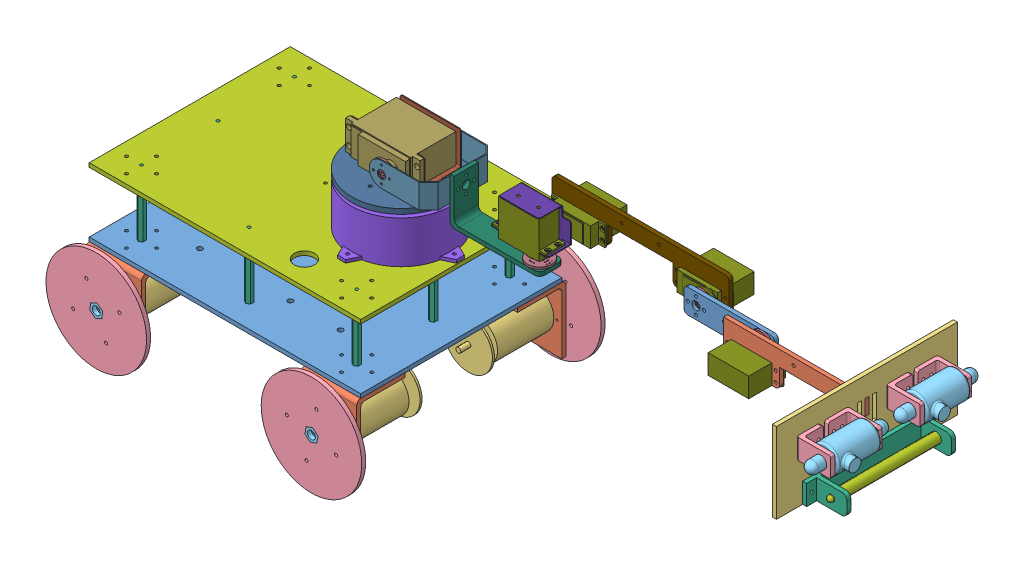
SolidWorks assembly robot, configuration Default. Lengths in mm.
Overall size (760.42 282.73 242).
55 component instances, 25 part files, 138 mates.
Components (placement in the parent):
- base_odroid_down_fix-1: base_odroid_down_fix [Default] at (39.4639 122.941 229.7749) x (1 0 0) z (0 -1 0) size (270 200 4)
- link_motor_1_port-1: link_motor_1_port [Default] at (221.3654 112.3394 287.3354) x (0 0 -1) z (1 0 0) size (48 66 56)
- motor_dc_NISCA-1: motor_dc_NISCA [Default] at (244.2642 39.7289 313.6416) x (0 -1 0) z (0 0 -1) size (54 48 92)
- roda_shaft-1: roda_shaft [Default] at (185.8398 121.6563 330.6416) x (-0.980223 0.197896 0) z (0 0 1) size (100 100 4)
- shaft_adapter_5mm-1: shaft_adapter_5mm [Default] at (248.7954 72.9583 317.6416) x (0.980223 -0.197896 0) z (0 0 1) size (12 13.86 17)
- link_motor_1_port-2: link_motor_1_port [Default] at (221.3654 112.3394 139.9479) x (0 0 1) z (-1 0 0) size (48 66 56)
- motor_dc_NISCA-2: motor_dc_NISCA [Default] at (198.4666 39.7289 113.6416) x (0 -1 0) z (0 0 1) size (54 48 92)
- shaft_adapter_5mm-3: shaft_adapter_5mm [Default] at (238.0112 59.5291 109.6416) x (0.404857 -0.91438 0) z (0 0 -1) size (12 13.86 17)
- roda_shaft-2: roda_shaft [Default] at (222.1063 135.748 96.6416) x (0.589448 0.807807 0) z (0 0 -1) size (100 100 4)
- link_motor_1_port-5: link_motor_1_port [Default] at (7.3654 112.3394 287.3354) x (0 0 -1) z (1 0 0) size (48 66 56)
- motor_dc_NISCA-5: motor_dc_NISCA [Default] at (-15.5334 128.1531 313.6416) x (0 1 0) z (0 0 -1) size (54 48 92)
- roda_shaft-5: roda_shaft [Default] at (51.5287 56.8466 334.6416) x (0.393495 -0.919327 0) z (0 0 -1) size (100 100 4)
- shaft_adapter_5mm-6: shaft_adapter_5mm [Default] at (0.8367 112.7577 317.6416) x (-0.393495 0.919327 0) z (0 0 1) size (12 13.86 17)
- link_motor_1_port-6: link_motor_1_port [Default] at (7.3654 112.3394 139.9479) x (0 0 1) z (-1 0 0) size (48 66 56)
- motor_dc_NISCA-6: motor_dc_NISCA [Default] at (-15.5334 39.7289 113.6416) x (0 -1 0) z (0 0 1) size (54 48 92)
- roda_shaft-6: roda_shaft [Default] at (45.258 48.6046 96.6416) x (0.202799 -0.97922 0) z (0 0 -1) size (100 100 4)
- shaft_adapter_5mm-7: shaft_adapter_5mm [Default] at (36.6325 79.8838 109.6416) x (0.949429 -0.313981 0) z (0 0 -1) size (12 13.86 17)
- spacer_6cm-2: spacer_6cm [Default] at (221.7099 182.941 288.7798) x (0.5 0 -0.866025) z (0 -1 0) size (6 6.93 68)
- spacer_6cm-3: spacer_6cm [Default] at (114.7099 182.941 288.7798) x (0.5 0 -0.866025) z (0 -1 0) size (6 6.93 68)
- spacer_6cm-4: spacer_6cm [Default] at (7.7099 182.941 288.7798) x (0.5 0 -0.866025) z (0 -1 0) size (6 6.93 68)
- spacer_6cm-5: spacer_6cm [Default] at (221.7099 182.941 212.7798) x (0.5 0 -0.866025) z (0 -1 0) size (6 6.93 68)
- spacer_6cm-7: spacer_6cm [Default] at (7.7099 182.941 212.7798) x (0.5 0 -0.866025) z (0 -1 0) size (6 6.93 68)
- spacer_6cm-8: spacer_6cm [Default] at (221.7099 182.941 136.7798) x (0.5 0 -0.866025) z (0 -1 0) size (6 6.93 68)
- spacer_6cm-9: spacer_6cm [Default] at (114.7099 182.941 136.7798) x (0.5 0 -0.866025) z (0 -1 0) size (6 6.93 68)
- spacer_6cm-10: spacer_6cm [Default] at (7.7099 182.941 136.7798) x (0.5 0 -0.866025) z (0 -1 0) size (6 6.93 68)
- base_odroid_up_fix-1: base_odroid_up_fix [Default] at (189.2669 186.941 197.5083) x (-1 0 0) z (0 -1 0) size (270 200 4)
- base_arm-1: base_arm [Default] at (189.3654 194.0898 219.4289) x (0 0 1) z (-1 0 0) size (118.01 42 118.01)
- servo_hs422-1: servo_hs422 [Default] at (199.6524 210.6756 203.7356) x (0 0 1) z (-1 0 0) size (19.81 42.14 58.23)
- link1_arm-1: link1_arm [Default] at (162.7148 232.0663 213.6416) x (-1 0 0) z (0 1 0) size (98 98 12)
- bracket_servo_hs755-1: bracket_servo_hs755 [Default] at (226.3654 266.4802 252.854) x (0 0 1) z (-1 0 0) size (44 34 74)
- servo_hs755-1: servo_hs755 [Default] at (199.4663 211.9363 188.6416) x (0 -1 0) z (0 0 1) size (29 74 56.99)
- servo_horn_general-1: servo_horn_general [Default] at (158.1724 253.8913 247.6316) x (-1 0 0) z (0 0 -1) size (24 24 6)
- link2_ubracket-2: link2_ubracket [Default] at (243.847 269.0663 202.3382) x (0 0 -1) z (0 -1 0) size (66 59 24)
- link2_fix-2: link2_fix [Default] at (302.1273 265.014 203.2174) x (0 1 0) z (0 0 1) size (45.14 89 24)
- servo_horn_general-2: servo_horn_general [Default] at (282.1724 229.0663 212.0424) x (-1 0 0) z (0 1 0) size (24 24 6)
- servo_hs645-2: servo_hs645 [Default] at (371.772 273.4208 228.4385) x (1 0 0) z (0 -1 0) size (53.34 19.56 42.35)
- bracket_servo_645-2: bracket_servo_645 [Default] at (346.6974 227.1529 209.3754) x (0 -1 0) z (-1 0 0) size (34 24 57)
- servo_horn_general-3: servo_horn_general [Default] at (280.7737 260.864 201.2504) x (-0.965926 0.258819 0) z (0 0 -1) size (24 24 6)
- servo_hs645-3: servo_hs645 [Default] at (283.7908 238.6247 156.8959) x (-1 0 0) z (0 0 1) size (53.34 19.56 42.35)
- link4_fix-1: link4_fix [Default] at (524.8795 244.4473 179.8199) size (176.25 35 4)
- servo_hs645-4: servo_hs645 [Default] at (511.566 264.5589 151.2449) size (53.34 19.56 42.35)
- link5_fix-1: link5_fix [Default] at (491.6097 296.6345 195.5994) x (0 1 0) z (0 0 1) size (24 90 4)
- servo_horn_general-4: servo_horn_general [Default] at (421.9664 248.1628 195.5994) x (-1 0 0) z (0 0 -1) size (24 24 6)
- servo_horn_general-5: servo_horn_general [Default] at (581.3523 248.1628 199.5994) size (24 24 6)
- servo_hs645-5: servo_hs645 [Default] at (491.7528 264.5589 243.9539) x (-1 0 0) z (0 0 -1) size (53.34 19.56 42.35)
- link6_eff-1: link6_eff [Default] at (498.4393 244.4473 221.0299) x (-1 0 0) z (0 0 -1) size (140.63 35 4)
- base_link_effector_fix-2: base_link_effector_fix [Default] at (654.1404 277.9299 221.7305) x (0 0 -1) z (1 0 0) size (180 80 4)
- base_webcam_fix1-2: base_webcam_fix1 [Default] at (658.1404 278.3128 289.0299) x (0 0 -1) z (0 -1 0) size (23 34 20)
- base_webcam_fix1-3: base_webcam_fix1 [Default] at (658.1404 258.3128 238.0299) x (0 0 1) z (0 1 0) size (23 34 20)
- base_webcam_fix1-4: base_webcam_fix1 [Default] at (658.1404 278.3128 200.0299) x (0 0 -1) z (0 -1 0) size (23 34 20)
- base_webcam_fix1-5: base_webcam_fix1 [Default] at (658.1404 258.3128 149.0299) x (0 0 1) z (0 1 0) size (23 34 20)
- webcam_sturdy-3: webcam_sturdy [Default] at (682.1404 268.3128 237.719) x (0 0 -1) z (1 0 0) size (79 27 33.5)
- webcam_sturdy-4: webcam_sturdy [Default] at (682.1404 268.3128 148.719) x (0 0 -1) z (1 0 0) size (79 27 33.5)
- base_GM-1: base_GM [Default] at (666.3876 236.8128 179.2981) x (0 0 -1) z (0 -1 0) size (128 34 20)
- tabung_GM-1: tabung_GM [Default] at (725.7739 219.5023 169.0299) x (0.998179 0.060316 0) z (0 0 1) size (10 10 116)
Mates (geometry in assembly coordinates):
- Coincident1: coincident anti-aligned: plane of link_motor_1_port-1 through (193.3654 52.941 313.6416) normal (0 0 -1); plane of motor_dc_NISCA-1 through (221.3654 83.941 313.6416) normal (0 0 1)
- Concentric1: concentric aligned: cylinder of link_motor_1_port-1 through (221.3654 83.941 317.6416) axis (0 0 -1) radius 9.5; cylinder of motor_dc_NISCA-1 through (221.3654 83.941 317.6416) axis (0 0 -1) radius 9
- Concentric2: concentric anti-aligned: cylinder of link_motor_1_port-1 through (221.3654 106.941 317.6416) axis (0 0 -1) radius 1; cylinder of motor_dc_NISCA-1 through (221.3654 106.941 311.6416) axis (0 0 1) radius 1.5
- Coincident2: coincident anti-aligned: plane of motor_dc_NISCA-1 through (244.2642 39.7289 317.6416) normal (0 0 1); plane of shaft_adapter_5mm-1 through (221.3654 83.941 317.6416) normal (0 0 -1)
- Concentric4: concentric aligned: cylinder of motor_dc_NISCA-1 through (221.3654 83.941 330.6416) axis (0 0 -1) radius 2.5; cylinder of shaft_adapter_5mm-1 through (221.3654 83.941 330.6416) axis (0 0 -1) radius 2.5
- Coincident3: coincident anti-aligned: plane of roda_shaft-1 through (222.7365 90.7322 330.6416) normal (0.318728 -0.947846 0); plane of shaft_adapter_5mm-1 through (222.7365 90.7322 334.6416) normal (-0.318728 0.947846 0)
- Coincident4: coincident aligned: plane of roda_shaft-1 through (221.3654 83.941 334.6416) normal (0 0 1); plane of shaft_adapter_5mm-1 through (248.7954 72.9583 334.6416) normal (0 0 1)
- Coincident7: coincident anti-aligned: plane of roda_shaft-1 through (214.7985 81.7328 330.6416) normal (0.661495 0.74995 0); plane of shaft_adapter_5mm-1 through (214.7985 81.7328 334.6416) normal (-0.661495 -0.74995 0)
- Coincident8: coincident anti-aligned: plane of link_motor_1_port-2 through (249.3654 52.941 113.6416) normal (0 0 1); plane of motor_dc_NISCA-2 through (221.3654 83.941 113.6416) normal (0 0 -1)
- Concentric5: concentric aligned: cylinder of link_motor_1_port-2 through (221.3654 83.941 109.6416) axis (0 0 1) radius 9.5; cylinder of motor_dc_NISCA-2 through (221.3654 83.941 109.6416) axis (0 0 1) radius 9
- Concentric7: concentric anti-aligned: cylinder of link_motor_1_port-2 through (221.3654 106.941 109.6416) axis (0 0 1) radius 1; cylinder of motor_dc_NISCA-2 through (221.3654 106.941 115.6416) axis (0 0 -1) radius 1.5
- Coincident9: coincident anti-aligned: plane of base_odroid_down_fix-1 through (39.4639 118.941 229.7749) normal (0 -1 0); plane of link_motor_1_port-1 through (193.3654 118.941 269.6416) normal (0 1 0)
- Concentric8: concentric anti-aligned: cylinder of base_odroid_down_fix-1 through (206.3654 118.941 289.6416) axis (0 1 0) radius 1.5; cylinder of link_motor_1_port-1 through (206.3654 118.941 289.6416) axis (0 -1 0) radius 1.5
- Concentric9: concentric anti-aligned: cylinder of base_odroid_down_fix-1 through (236.3654 118.941 289.6416) axis (0 1 0) radius 1.5; cylinder of link_motor_1_port-1 through (236.3654 118.941 289.6416) axis (0 -1 0) radius 1.5
- Coincident11: coincident aligned: plane of shaft_adapter_5mm-3 through (238.0112 59.5291 92.6416) normal (0 0 -1); plane of roda_shaft-2 through (221.3654 83.941 92.6416) normal (0 0 -1)
- Coincident12: coincident anti-aligned: plane of shaft_adapter_5mm-3 through (220.627 77.0523 92.6416) normal (-0.589448 -0.807807 0); plane of roda_shaft-2 through (220.627 77.0523 96.6416) normal (0.589448 0.807807 0)
- Coincident13: coincident anti-aligned: plane of shaft_adapter_5mm-3 through (227.7004 86.746 92.6416) normal (0.994305 -0.106573 0); plane of roda_shaft-2 through (227.7004 86.746 96.6416) normal (-0.994305 0.106573 0)
- Coincident14: coincident anti-aligned: plane of motor_dc_NISCA-2 through (198.4666 39.7289 109.6416) normal (0 0 -1); plane of shaft_adapter_5mm-3 through (221.3654 83.941 109.6416) normal (0 0 1)
- Concentric10: concentric aligned: cylinder of motor_dc_NISCA-2 through (221.3654 83.941 96.6416) axis (0 0 1) radius 2.5; cylinder of shaft_adapter_5mm-3 through (221.3654 83.941 96.6416) axis (0 0 1) radius 2.5
- Coincident15: coincident anti-aligned: plane of base_odroid_down_fix-1 through (39.4639 118.941 229.7749) normal (0 -1 0); plane of link_motor_1_port-2 through (249.3654 118.941 157.6416) normal (0 1 0)
- Concentric11: concentric anti-aligned: cylinder of base_odroid_down_fix-1 through (206.3654 118.941 137.6416) axis (0 1 0) radius 1.5; cylinder of link_motor_1_port-2 through (206.3654 118.941 137.6416) axis (0 -1 0) radius 1.5
- Concentric12: concentric anti-aligned: cylinder of base_odroid_down_fix-1 through (236.3654 118.941 137.6416) axis (0 1 0) radius 1.5; cylinder of link_motor_1_port-2 through (236.3654 118.941 137.6416) axis (0 -1 0) radius 1.5
- Coincident16: coincident anti-aligned: plane of link_motor_1_port-5 through (-20.6346 52.941 313.6416) normal (0 0 -1); plane of motor_dc_NISCA-5 through (7.3654 83.941 313.6416) normal (0 0 1)
- Concentric13: concentric aligned: cylinder of link_motor_1_port-5 through (7.3654 83.941 317.6416) axis (0 0 -1) radius 9.5; cylinder of motor_dc_NISCA-5 through (7.3654 83.941 317.6416) axis (0 0 -1) radius 9
- Concentric14: concentric anti-aligned: cylinder of link_motor_1_port-5 through (7.3654 106.941 317.6416) axis (0 0 -1) radius 1; cylinder of motor_dc_NISCA-5 through (7.3654 106.941 311.6416) axis (0 0 1) radius 1.5
- Concentric16: concentric aligned: cylinder of motor_dc_NISCA-5 through (7.3654 83.941 330.6416) axis (0 0 -1) radius 2.5; cylinder of shaft_adapter_5mm-6 through (7.3654 83.941 330.6416) axis (0 0 -1) radius 2.5
- Coincident17: coincident anti-aligned: plane of motor_dc_NISCA-5 through (-15.5334 128.1531 317.6416) normal (0 0 1); plane of shaft_adapter_5mm-6 through (7.3654 83.941 317.6416) normal (0 0 -1)
- Coincident18: coincident anti-aligned: plane of roda_shaft-5 through (6.5417 77.062 334.6416) normal (0.599413 0.80044 0); plane of shaft_adapter_5mm-6 through (0.9961 81.2148 334.6416) normal (-0.599413 -0.80044 0)
- Coincident19: coincident aligned: plane of roda_shaft-5 through (7.3654 83.941 334.6416) normal (0 0 1); plane of shaft_adapter_5mm-6 through (0.8367 112.7577 334.6416) normal (0 0 1)
- Coincident20: coincident anti-aligned: plane of roda_shaft-5 through (1.8198 88.0939 334.6416) normal (0.393495 -0.919327 0); plane of shaft_adapter_5mm-6 through (8.1891 90.8201 334.6416) normal (-0.393495 0.919327 0)
- Coincident21: coincident anti-aligned: plane of base_odroid_down_fix-1 through (39.4639 118.941 229.7749) normal (0 -1 0); plane of link_motor_1_port-5 through (-20.6346 118.941 269.6416) normal (0 1 0)
- Concentric17: concentric anti-aligned: cylinder of base_odroid_down_fix-1 through (-7.6346 118.941 289.6416) axis (0 1 0) radius 1.5; cylinder of link_motor_1_port-5 through (-7.6346 118.941 289.6416) axis (0 -1 0) radius 1.5
- Concentric18: concentric anti-aligned: cylinder of base_odroid_down_fix-1 through (22.3654 118.941 289.6416) axis (0 1 0) radius 1.5; cylinder of link_motor_1_port-5 through (22.3654 118.941 289.6416) axis (0 -1 0) radius 1.5
- Coincident22: coincident anti-aligned: plane of link_motor_1_port-6 through (35.3654 52.941 113.6416) normal (0 0 1); plane of motor_dc_NISCA-6 through (7.3654 83.941 113.6416) normal (0 0 -1)
- Concentric19: concentric aligned: cylinder of link_motor_1_port-6 through (7.3654 83.941 109.6416) axis (0 0 1) radius 9.5; cylinder of motor_dc_NISCA-6 through (7.3654 83.941 109.6416) axis (0 0 1) radius 9
- Concentric20: concentric anti-aligned: cylinder of link_motor_1_port-6 through (7.3654 106.941 109.6416) axis (0 0 1) radius 1; cylinder of motor_dc_NISCA-6 through (7.3654 106.941 115.6416) axis (0 0 -1) radius 1.5
- Concentric21: concentric aligned: cylinder of motor_dc_NISCA-6 through (7.3654 83.941 96.6416) axis (0 0 1) radius 2.5; cylinder of shaft_adapter_5mm-7 through (7.3654 83.941 96.6416) axis (0 0 1) radius 2.5
- Coincident23: coincident anti-aligned: plane of motor_dc_NISCA-6 through (-15.5334 39.7289 109.6416) normal (0 0 -1); plane of shaft_adapter_5mm-7 through (7.3654 83.941 109.6416) normal (0 0 1)
- Coincident24: coincident aligned: plane of roda_shaft-6 through (7.3654 83.941 92.6416) normal (0 0 -1); plane of shaft_adapter_5mm-7 through (36.6325 79.8838 92.6416) normal (0 0 -1)
- Coincident25: coincident anti-aligned: plane of roda_shaft-6 through (2.7565 89.1138 96.6416) normal (0.202799 -0.97922 0); plane of shaft_adapter_5mm-7 through (2.7565 89.1138 92.6416) normal (-0.202799 0.97922 0)
- Coincident26: coincident anti-aligned: plane of roda_shaft-6 through (5.1901 77.3632 96.6416) normal (0.74663 0.665239 0); plane of shaft_adapter_5mm-7 through (5.1901 77.3632 92.6416) normal (-0.74663 -0.665239 0)
- Coincident27: coincident anti-aligned: plane of base_odroid_down_fix-1 through (39.4639 118.941 229.7749) normal (0 -1 0); plane of link_motor_1_port-6 through (35.3654 118.941 157.6416) normal (0 1 0)
- Concentric22: concentric anti-aligned: cylinder of base_odroid_down_fix-1 through (-7.6346 118.941 137.6416) axis (0 1 0) radius 1.5; cylinder of link_motor_1_port-6 through (-7.6346 118.941 137.6416) axis (0 -1 0) radius 1.5
- Concentric23: concentric anti-aligned: cylinder of base_odroid_down_fix-1 through (22.3654 118.941 137.6416) axis (0 1 0) radius 1.5; cylinder of link_motor_1_port-6 through (22.3654 118.941 137.6416) axis (0 -1 0) radius 1.5
- Concentric24: concentric aligned: cylinder of base_odroid_down_fix-1 through (221.3654 118.941 289.6416) axis (0 1 0) radius 1.5; cylinder of spacer_6cm-2 through (221.3654 118.941 289.6416) axis (0 1 0) radius 1.5
- Coincident28: coincident anti-aligned: plane of base_odroid_down_fix-1 through (39.4639 122.941 229.7749) normal (0 1 0); plane of spacer_6cm-2 through (221.7099 122.941 288.7798) normal (0 -1 0)
- Parallel2: parallel aligned: plane of base_odroid_down_fix-1 through (249.3654 118.941 229.7749) normal (1 0 0); plane of spacer_6cm-2 through (224.3654 122.941 287.9096) normal (1 0 0)
- Concentric25: concentric anti-aligned: cylinder of spacer_6cm-2 through (221.3654 186.941 289.6416) axis (0 -1 0) radius 1.5; cylinder of base_odroid_up_fix-1 through (221.3654 182.941 289.6416) axis (0 1 0) radius 1.5
- Concentric26: concentric anti-aligned: cylinder of spacer_6cm-7 through (7.3654 186.941 213.6416) axis (0 -1 0) radius 1.5; cylinder of base_odroid_up_fix-1 through (7.3654 182.941 213.6416) axis (0 1 0) radius 1.5
- Coincident29: coincident anti-aligned: plane of spacer_6cm-2 through (221.7099 182.941 288.7798) normal (0 1 0); plane of base_odroid_up_fix-1 through (189.2669 182.941 197.5083) normal (0 -1 0)
- Coincident31: coincident anti-aligned: plane of base_arm-1 through (189.3654 225.941 213.6416) normal (0 -1 0); plane of servo_hs422-1 through (199.6524 225.941 203.7356) normal (0 1 0)
- Parallel3: parallel aligned: plane of base_odroid_up_fix-1 through (249.3654 182.941 197.5083) normal (1 0 0); plane of servo_hs422-1 through (219.5914 210.6756 223.5476) normal (1 0 0)
- Coincident33: coincident anti-aligned: plane of base_odroid_up_fix-1 through (189.2669 186.941 197.5083) normal (0 1 0); plane of base_arm-1 through (189.3654 186.941 259.6416) normal (0 -1 0)
- Concentric28: concentric anti-aligned: cylinder of base_odroid_up_fix-1 through (242.3654 182.941 213.6416) axis (0 1 0) radius 1.5; cylinder of base_arm-1 through (242.3654 189.941 213.6416) axis (0 -1 0) radius 1.5
- Concentric29: concentric anti-aligned: cylinder of base_odroid_up_fix-1 through (189.3654 182.941 160.6416) axis (0 1 0) radius 1.5; cylinder of base_arm-1 through (189.3654 189.941 160.6416) axis (0 -1 0) radius 1.5
- Parallel5: parallel aligned: plane of base_odroid_up_fix-1 through (189.2669 182.941 113.6416) normal (0 0 -1); plane of servo_hs422-1 through (199.6524 210.6756 203.7356) normal (0 0 -1)
- Concentric30: concentric aligned: cylinder of base_arm-1 through (189.3654 225.941 213.6416) axis (0 1 0) radius 5.4623; cylinder of servo_hs422-1 through (189.3654 202.0734 213.6416) axis (0 1 0) radius 6.4897
- Concentric31: concentric aligned: cylinder of servo_hs422-1 through (189.3654 212.8107 213.6416) axis (0 1 0) radius 2.8131; cylinder of link1_arm-1 through (189.3654 228.0663 213.6416) axis (0 1 0) radius 3
- Coincident36: coincident anti-aligned: plane of servo_hs422-1 through (199.6524 232.0663 223.5476) normal (0 1 0); plane of link1_arm-1 through (189.3654 232.0663 213.6416) normal (0 -1 0)
- Concentric32: concentric aligned: cylinder of link1_arm-1 through (189.3654 240.0663 213.6416) axis (0 -1 0) radius 4; cylinder of bracket_servo_hs755-1 through (189.3654 238.0663 213.6416) axis (0 -1 0) radius 4
- Coincident38: coincident anti-aligned: plane of link1_arm-1 through (189.3654 237.0663 213.6416) normal (0 1 0); plane of bracket_servo_hs755-1 through (152.3654 237.0663 183.6416) normal (0 -1 0)
- Concentric33: concentric anti-aligned: cylinder of link1_arm-1 through (181.3654 232.0663 213.6416) axis (0 1 0) radius 1.5; cylinder of bracket_servo_hs755-1 through (181.3654 238.0663 213.6416) axis (0 -1 0) radius 1.5
- Coincident40: coincident anti-aligned: plane of bracket_servo_hs755-1 through (152.3654 237.0663 227.6416) normal (0 0 1); plane of servo_hs755-1 through (199.4663 211.9363 227.6416) normal (0 0 -1)
- Concentric36: concentric aligned: cylinder of bracket_servo_hs755-1 through (155.3654 248.5663 226.6416) axis (0 0 1) radius 1.5; cylinder of servo_hs755-1 through (155.3654 248.5663 227.6416) axis (0 0 1) radius 2.5
- Concentric37: concentric aligned: cylinder of bracket_servo_hs755-1 through (223.3654 264.5663 226.6416) axis (0 0 1) radius 1.5; cylinder of servo_hs755-1 through (223.3654 264.5663 227.6416) axis (0 0 1) radius 2.5
- Concentric39: concentric anti-aligned: cylinder of servo_hs755-1 through (204.8654 257.0663 245.6316) axis (0 0 -1) radius 3; cylinder of servo_horn_general-1 through (204.8654 257.0663 242.6316) axis (0 0 1) radius 3
- Coincident41: coincident anti-aligned: plane of servo_hs755-1 through (204.8654 257.0663 245.6316) normal (0 0 1); plane of servo_horn_general-1 through (204.8654 257.0663 245.6316) normal (0 0 -1)
- Concentric40: concentric anti-aligned: cylinder of servo_horn_general-1 through (204.8654 257.0663 248.6316) axis (0 0 -1) radius 4; cylinder of link2_ubracket-2 through (204.8654 257.0663 247.6316) axis (0 0 1) radius 4
- Coincident42: coincident anti-aligned: plane of servo_horn_general-1 through (204.8654 257.0663 247.6316) normal (0 0 1); plane of link2_ubracket-2 through (242.037 245.0663 247.6316) normal (0 0 -1)
- Concentric41: concentric aligned: cylinder of servo_horn_general-1 through (204.8654 265.0663 245.6316) axis (0 0 1) radius 0.5; cylinder of link2_ubracket-2 through (204.8654 265.0663 247.6316) axis (0 0 1) radius 1
- Coincident46: coincident anti-aligned: plane of link2_ubracket-2 through (251.8654 245.0663 239.2174) normal (1 0 0); plane of link2_fix-2 through (251.8654 265.014 227.2174) normal (-1 0 0)
- Concentric45: concentric anti-aligned: cylinder of link2_ubracket-2 through (250.8654 257.0663 215.2174) axis (1 0 0) radius 4; cylinder of link2_fix-2 through (255.8654 257.0663 215.2174) axis (-1 0 0) radius 4
- Concentric46: concentric anti-aligned: cylinder of link2_ubracket-2 through (250.8654 257.0663 207.2174) axis (1 0 0) radius 1; cylinder of link2_fix-2 through (255.8654 257.0663 207.2174) axis (-1 0 0) radius 1.5
- Coincident47: coincident anti-aligned: plane of servo_horn_general-2 through (328.8654 231.0663 215.2174) normal (0 1 0); plane of servo_hs645-2 through (328.8654 231.0663 215.2174) normal (0 -1 0)
- Concentric48: concentric anti-aligned: cylinder of servo_horn_general-2 through (328.8654 234.0663 215.2174) axis (0 -1 0) radius 3; cylinder of servo_hs645-2 through (328.8654 231.0663 215.2174) axis (0 1 0) radius 2.9972
- Coincident48: coincident anti-aligned: plane of link2_fix-2 through (302.1273 229.0663 227.2174) normal (0 1 0); plane of servo_horn_general-2 through (328.8654 229.0663 215.2174) normal (0 -1 0)
- Concentric49: concentric anti-aligned: cylinder of link2_fix-2 through (328.8654 229.0663 215.2174) axis (0 -1 0) radius 4; cylinder of servo_horn_general-2 through (328.8654 228.0663 215.2174) axis (0 1 0) radius 4
- Concentric50: concentric aligned: cylinder of link2_fix-2 through (328.8654 229.0663 207.2174) axis (0 -1 0) radius 1.5; cylinder of servo_horn_general-2 through (328.8654 231.0663 207.2174) axis (0 -1 0) radius 0.5
- Coincident50: coincident anti-aligned: plane of servo_hs645-2 through (371.772 244.8458 228.4385) normal (0 -1 0); plane of bracket_servo_645-2 through (289.6974 244.8458 202.2504) normal (0 1 0)
- Concentric51: concentric aligned: cylinder of servo_hs645-2 through (342.3274 248.0208 220.5514) axis (0 -1 0) radius 2.5019; cylinder of bracket_servo_645-2 through (342.3274 246.3858 220.5514) axis (0 -1 0) radius 1.5
- Concentric52: concentric aligned: cylinder of servo_hs645-2 through (294.0674 248.0208 220.5514) axis (0 -1 0) radius 2.5019; cylinder of bracket_servo_645-2 through (294.0674 246.3858 220.5514) axis (0 -1 0) radius 1.5
- Concentric53: concentric aligned: cylinder of bracket_servo_645-2 through (326.6974 251.8458 202.2504) axis (0 0 -1) radius 4; cylinder of servo_horn_general-3 through (326.6974 251.8458 202.2504) axis (0 0 -1) radius 4
- Coincident51: coincident anti-aligned: plane of bracket_servo_645-2 through (289.6974 273.8458 201.2504) normal (0 0 -1); plane of servo_horn_general-3 through (326.6974 251.8458 201.2504) normal (0 0 1)
- Concentric54: concentric anti-aligned: cylinder of bracket_servo_645-2 through (326.6974 259.8458 202.2504) axis (0 0 -1) radius 1.5; cylinder of servo_horn_general-3 through (326.6974 259.8458 199.2504) axis (0 0 1) radius 0.5
- Coincident52: coincident anti-aligned: plane of servo_horn_general-3 through (326.6974 251.8458 199.2504) normal (0 0 -1); plane of servo_hs645-3 through (326.6974 251.8458 199.2504) normal (0 0 1)
- Concentric55: concentric anti-aligned: cylinder of servo_horn_general-3 through (326.6974 251.8458 196.2504) axis (0 0 1) radius 3; cylinder of servo_hs645-3 through (326.6974 251.8458 199.2504) axis (0 0 -1) radius 2.9972
- Concentric61: concentric anti-aligned: cylinder of servo_hs645-4 through (468.6594 251.3378 193.5994) axis (0 0 -1) radius 2.9972; cylinder of servo_horn_general-4 through (468.6594 251.3378 190.5994) axis (0 0 1) radius 3
- Coincident56: coincident anti-aligned: plane of servo_hs645-4 through (468.6594 251.3378 193.5994) normal (0 0 1); plane of servo_horn_general-4 through (468.6594 251.3378 193.5994) normal (0 0 -1)
- Coincident57: coincident anti-aligned: plane of link5_fix-1 through (491.6097 296.6345 195.5994) normal (0 0 -1); plane of servo_horn_general-4 through (468.6594 251.3378 195.5994) normal (0 0 1)
- Concentric62: concentric anti-aligned: cylinder of link5_fix-1 through (468.6594 251.3378 195.5994) axis (0 0 1) radius 4; cylinder of servo_horn_general-4 through (468.6594 251.3378 196.5994) axis (0 0 -1) radius 4
- Concentric63: concentric aligned: cylinder of link5_fix-1 through (468.6594 259.3378 195.5994) axis (0 0 1) radius 1.5; cylinder of servo_horn_general-4 through (468.6594 259.3378 193.5994) axis (0 0 1) radius 0.5
- Concentric64: concentric anti-aligned: cylinder of servo_horn_general-5 through (534.6594 251.3378 204.5994) axis (0 0 -1) radius 3; cylinder of servo_hs645-5 through (534.6594 251.3378 201.5994) axis (0 0 1) radius 2.9972
- Coincident58: coincident anti-aligned: plane of servo_horn_general-5 through (534.6594 251.3378 201.5994) normal (0 0 1); plane of servo_hs645-5 through (534.6594 251.3378 201.5994) normal (0 0 -1)
- Coincident59: coincident anti-aligned: plane of link5_fix-1 through (491.6097 296.6345 199.5994) normal (0 0 1); plane of servo_horn_general-5 through (534.6594 251.3378 199.5994) normal (0 0 -1)
- Concentric65: concentric aligned: cylinder of link5_fix-1 through (534.6594 251.3378 195.5994) axis (0 0 1) radius 4; cylinder of servo_horn_general-5 through (534.6594 251.3378 198.5994) axis (0 0 1) radius 4
- Concentric66: concentric anti-aligned: cylinder of link5_fix-1 through (534.6594 243.3378 195.5994) axis (0 0 1) radius 1.5; cylinder of servo_horn_general-5 through (534.6594 243.3378 201.5994) axis (0 0 -1) radius 0.5
- Coincident60: coincident anti-aligned: plane of servo_hs645-5 through (491.7528 264.5589 217.0299) normal (0 0 1); plane of link6_eff-1 through (498.4393 244.4473 217.0299) normal (0 0 -1)
- Concentric67: concentric aligned: cylinder of servo_hs645-5 through (521.1974 246.5118 218.5539) axis (0 0 -1) radius 2.5019; cylinder of link6_eff-1 through (521.1974 246.5118 221.0299) axis (0 0 -1) radius 1.5
- Concentric68: concentric aligned: cylinder of servo_hs645-5 through (569.4574 246.5118 218.5539) axis (0 0 -1) radius 2.5019; cylinder of link6_eff-1 through (569.4574 246.5118 221.0299) axis (0 0 -1) radius 1.5
- Coincident61: coincident aligned: plane of link6_eff-1 through (658.1404 244.4473 217.0299) normal (1 0 0); plane of base_link_effector_fix-2 through (658.1404 277.9299 221.7305) normal (1 0 0)
- Coincident62: coincident anti-aligned: plane of link6_eff-1 through (498.4393 244.4473 217.0299) normal (0 0 -1); plane of base_link_effector_fix-2 through (654.1404 276.8128 217.0299) normal (0 0 1)
- Coincident63: coincident anti-aligned: plane of link6_eff-1 through (498.4393 276.8128 217.0299) normal (0 1 0); plane of base_link_effector_fix-2 through (654.1404 276.8128 221.0299) normal (0 -1 0)
- Coincident72: coincident anti-aligned: plane of base_link_effector_fix-2 through (658.1404 277.9299 221.7305) normal (1 0 0); plane of base_webcam_fix1-2 through (658.1404 258.3128 289.0299) normal (-1 0 0)
- Concentric71: concentric anti-aligned: cylinder of base_link_effector_fix-2 through (658.1404 268.3128 271.0299) axis (-1 0 0) radius 1.5; cylinder of base_webcam_fix1-2 through (658.1404 268.3128 271.0299) axis (1 0 0) radius 1.5
- Concentric72: concentric anti-aligned: cylinder of base_link_effector_fix-2 through (658.1404 268.3128 279.0299) axis (-1 0 0) radius 1.5; cylinder of base_webcam_fix1-2 through (658.1404 268.3128 279.0299) axis (1 0 0) radius 1.5
- Coincident73: coincident anti-aligned: plane of base_link_effector_fix-2 through (658.1404 277.9299 221.7305) normal (1 0 0); plane of base_webcam_fix1-3 through (658.1404 278.3128 238.0299) normal (-1 0 0)
- Concentric73: concentric anti-aligned: cylinder of base_link_effector_fix-2 through (658.1404 268.3128 248.0299) axis (-1 0 0) radius 1.5; cylinder of base_webcam_fix1-3 through (658.1404 268.3128 248.0299) axis (1 0 0) radius 1.5
- Concentric74: concentric anti-aligned: cylinder of base_link_effector_fix-2 through (658.1404 268.3128 256.0299) axis (-1 0 0) radius 1.5; cylinder of base_webcam_fix1-3 through (658.1404 268.3128 256.0299) axis (1 0 0) radius 1.5
- Coincident74: coincident anti-aligned: plane of base_link_effector_fix-2 through (658.1404 277.9299 221.7305) normal (1 0 0); plane of base_webcam_fix1-4 through (658.1404 258.3128 200.0299) normal (-1 0 0)
- Concentric75: concentric anti-aligned: cylinder of base_link_effector_fix-2 through (658.1404 268.3128 182.0299) axis (-1 0 0) radius 1.5; cylinder of base_webcam_fix1-4 through (658.1404 268.3128 182.0299) axis (1 0 0) radius 1.5
- Concentric76: concentric anti-aligned: cylinder of base_link_effector_fix-2 through (658.1404 268.3128 190.0299) axis (-1 0 0) radius 1.5; cylinder of base_webcam_fix1-4 through (658.1404 268.3128 190.0299) axis (1 0 0) radius 1.5
- Coincident75: coincident anti-aligned: plane of base_link_effector_fix-2 through (658.1404 277.9299 221.7305) normal (1 0 0); plane of base_webcam_fix1-5 through (658.1404 278.3128 149.0299) normal (-1 0 0)
- Concentric77: concentric anti-aligned: cylinder of base_link_effector_fix-2 through (658.1404 268.3128 167.0299) axis (-1 0 0) radius 1.5; cylinder of base_webcam_fix1-5 through (658.1404 268.3128 167.0299) axis (1 0 0) radius 1.5
- Concentric78: concentric anti-aligned: cylinder of base_link_effector_fix-2 through (658.1404 268.3128 159.0299) axis (-1 0 0) radius 1.5; cylinder of base_webcam_fix1-5 through (658.1404 268.3128 159.0299) axis (1 0 0) radius 1.5
- Concentric79: concentric anti-aligned: cylinder of base_webcam_fix1-2 through (682.1404 268.3128 285.0299) axis (0 0 1) radius 6; cylinder of webcam_sturdy-3 through (682.1404 268.3128 303.0299) axis (0 0 -1) radius 6
- Coincident78: coincident anti-aligned: plane of base_webcam_fix1-3 through (662.1404 278.3128 242.0299) normal (0 0 1); plane of webcam_sturdy-3 through (682.1404 268.3128 242.0299) normal (0 0 -1)
- Parallel8: parallel aligned: plane of base_link_effector_fix-2 through (658.1404 277.9299 221.7305) normal (1 0 0); plane of webcam_sturdy-3 through (702.1404 268.3128 275.0299) normal (1 0 0)
- Concentric80: concentric anti-aligned: cylinder of base_webcam_fix1-4 through (682.1404 268.3128 196.0299) axis (0 0 1) radius 6; cylinder of webcam_sturdy-4 through (682.1404 268.3128 214.0299) axis (0 0 -1) radius 6
- Coincident80: coincident anti-aligned: plane of base_webcam_fix1-5 through (662.1404 278.3128 153.0299) normal (0 0 1); plane of webcam_sturdy-4 through (682.1404 268.3128 153.0299) normal (0 0 -1)
- Parallel9: parallel aligned: plane of base_link_effector_fix-2 through (658.1404 277.9299 221.7305) normal (1 0 0); plane of webcam_sturdy-4 through (702.1404 268.3128 186.0299) normal (1 0 0)
- Coincident82: coincident anti-aligned: plane of base_link_effector_fix-2 through (658.1404 277.9299 221.7305) normal (1 0 0); plane of base_GM-1 through (658.1404 216.8128 273.0299) normal (-1 0 0)
- Concentric81: concentric anti-aligned: cylinder of base_link_effector_fix-2 through (658.1404 226.8128 160.0299) axis (-1 0 0) radius 1.5; cylinder of base_GM-1 through (658.1404 226.8128 160.0299) axis (1 0 0) radius 1.5
- Concentric82: concentric anti-aligned: cylinder of base_link_effector_fix-2 through (658.1404 226.8128 278.0299) axis (-1 0 0) radius 1.5; cylinder of base_GM-1 through (658.1404 226.8128 278.0299) axis (1 0 0) radius 1.5
- Concentric83: concentric anti-aligned: cylinder of base_GM-1 through (677.1404 226.8128 169.0299) axis (0 0 -1) radius 3; cylinder of tabung_GM-1 through (677.1404 226.8128 161.0299) axis (0 0 1) radius 3
- Coincident83: coincident anti-aligned: plane of base_GM-1 through (692.1404 216.8128 269.0299) normal (0 0 -1); plane of tabung_GM-1 through (677.1404 226.8128 269.0299) normal (0 0 1)
- LimitAngle1: limit planar angle = 1.570796 rad anti-aligned: plane of servo_hs755-1 through (218.8654 271.0663 231.6416) normal (1 0 0); plane of base_odroid_up_fix-1 through (189.2669 182.941 113.6416) normal (0 0 -1)
- LimitAngle2: limit planar angle = 0 rad aligned: plane of link2_ubracket-2 through (243.847 269.0663 202.3382) normal (0 1 0); plane of servo_hs755-1 through (218.8654 271.0663 231.6416) normal (0 1 0)
- LimitAngle3: limit planar angle = 1.570796 rad aligned: plane of servo_hs645-2 through (298.0044 246.4968 225.2504) normal (-1 0 0); plane of link2_fix-2 through (302.1273 265.014 203.2174) normal (0 0 -1)
- LimitAngle4: limit planar angle = 1.570796 rad anti-aligned: plane of link2_fix-2 through (302.1273 229.0663 227.2174) normal (0 1 0); plane of link4_fix-1 through (309.5524 244.4473 183.8199) normal (-1 0 0)
- Coincident84: coincident anti-aligned: plane of servo_hs645-3 through (283.7908 238.6247 183.8199) normal (0 0 -1); plane of link4_fix-1 through (524.8795 244.4473 183.8199) normal (0 0 1)
- Concentric84: concentric aligned: cylinder of servo_hs645-3 through (313.2354 256.6718 182.2959) axis (0 0 1) radius 2.5019; cylinder of link4_fix-1 through (313.2354 256.6718 179.8199) axis (0 0 1) radius 1.5
- Concentric85: concentric aligned: cylinder of servo_hs645-3 through (361.4954 246.5118 182.2959) axis (0 0 1) radius 2.5019; cylinder of link4_fix-1 through (361.4954 246.5118 179.8199) axis (0 0 1) radius 1.5
- Coincident85: coincident anti-aligned: plane of link4_fix-1 through (524.8795 244.4473 179.8199) normal (0 0 -1); plane of servo_hs645-4 through (511.566 264.5589 179.8199) normal (0 0 1)
- Concentric86: concentric aligned: cylinder of link4_fix-1 through (482.1214 246.5118 179.8199) axis (0 0 1) radius 1.5; cylinder of servo_hs645-4 through (482.1214 246.5118 176.6449) axis (0 0 1) radius 2.5019
- Concentric87: concentric aligned: cylinder of link4_fix-1 through (433.8614 256.6718 179.8199) axis (0 0 1) radius 1.5; cylinder of servo_hs645-4 through (433.8614 256.6718 176.6449) axis (0 0 1) radius 2.5019
- LimitAngle6: limit planar angle = 1.570796 rad anti-aligned: plane of link4_fix-1 through (309.5524 244.4473 183.8199) normal (-1 0 0); plane of link2_fix-2 through (302.1273 229.0663 227.2174) normal (0 1 0)
- LimitAngle7: limit planar angle = 1.570796 rad anti-aligned: plane of link5_fix-1 through (456.6594 239.3378 199.5994) normal (-1 0 0); plane of link4_fix-1 through (524.8795 276.8128 183.8199) normal (0 1 0)
- LimitAngle8: limit planar angle = 1.570796 rad aligned: plane of link6_eff-1 through (517.5144 244.4473 217.0299) normal (-1 0 0); plane of link5_fix-1 through (456.6594 263.3378 199.5994) normal (0 1 0)
